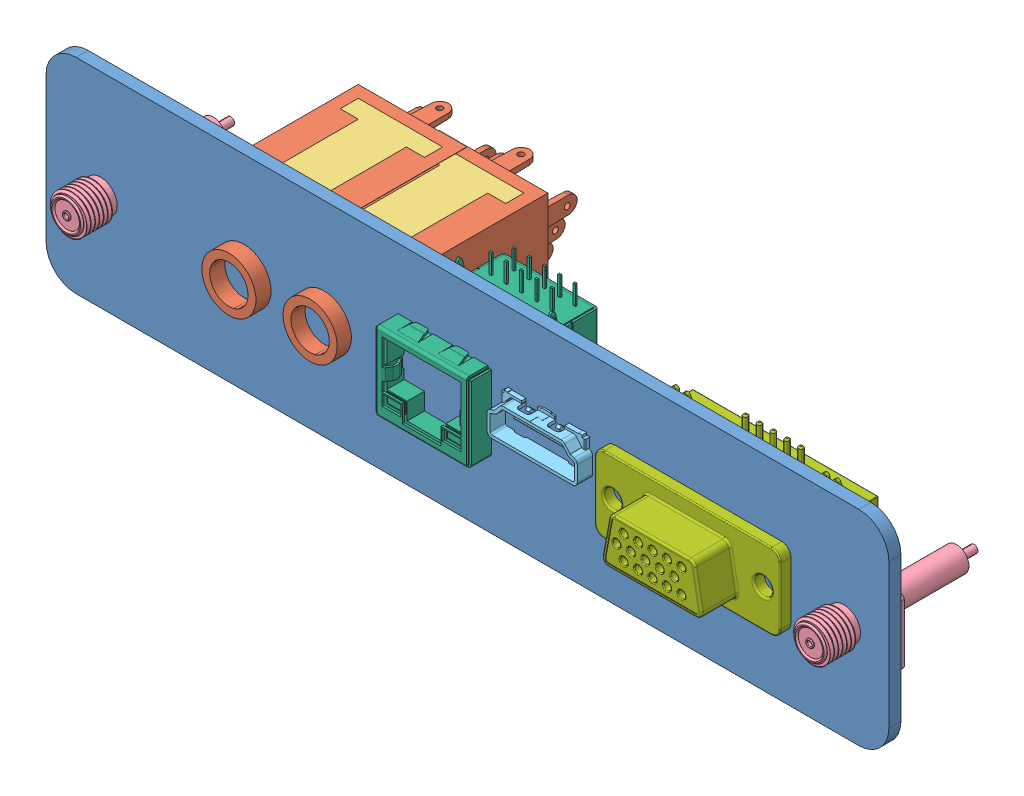
SolidWorks assembly mini computer back panel, configuration Default. Lengths in mm.
Overall size (140 34 41.82).
12 component instances, 7 part files, 10 mates.
Components (placement in the parent):
- mini computer enclosure sides-1: mini computer enclosure sides [Default] at (57.49 77.4023 100.7509) size (140 34 2)
- 6.35mm jack-1: 6.35mm jack [Default] at (20.382 76.9675 85.7703) size (19 18 36.5)
  - 6.35mm jack-1: 6.35mm jack [Default] at origin size (18 18 36.5)
  - Gnd Plate_6.35mm jack-1: Gnd Plate_6.35mm jack [Default] at (0 0 10) size (17 18 20)
- 6.35mm jack-2: 6.35mm jack [Default] at (33.7137 76.9223 85.6106) size (19 18 36.5)
  - 6.35mm jack-1: 6.35mm jack [Default] at origin size (18 18 36.5)
  - Gnd Plate_6.35mm jack-1: Gnd Plate_6.35mm jack [Default] at (0 0 10) size (17 18 20)
- Conector SMA flange 4 furos-1: Conector SMA flange 4 furos [Valor predeterminado] at (-3.4215 76.4747 99.0509) x (1 0 0) z (0 -1 0) size (12.7 27.4 12.7)
- Conector SMA flange 4 furos-2: Conector SMA flange 4 furos [Valor predeterminado] at (120.0439 76.6956 99.0509) x (1 0 0) z (0 -1 0) size (12.7 27.4 12.7)
- hdmi female-2: hdmi female [Default] at (70.798 82.8969 105.3066) x (-1 0 0) z (0 0 1) size (15.14 8.38 12.15)
- RJ45_10P_TJ3009-1: RJ45_10P_TJ3009 [Default] at (53.5571 84.0699 95.5036) x (-1 0 0) z (0 0 1) size (16 15.87 21.5)
- VGA PORT-1: VGA PORT [По умолчанию] at (95.8113 77.1031 104.5295) x (1 0 0) z (0 0 -1) size (30.8 16.47 22.2)
Mates (geometry in assembly coordinates):
- Coincident1: coincident anti-aligned: plane of mini computer enclosure sides-1 through (122.49 89.4023 100.7509) normal (0 0 -1); plane of Conector SMA flange 4 furos-2 through (120.0439 76.6956 100.7509) normal (0 0 1)
- Coincident2: coincident anti-aligned: plane of mini computer enclosure sides-1 through (122.49 89.4023 100.7509) normal (0 0 -1); plane of Conector SMA flange 4 furos-1 through (-3.4215 76.4747 100.7509) normal (0 0 1)
- Parallel1: parallel aligned: plane of Conector SMA flange 4 furos-1 through (-3.4215 76.4747 99.0509) normal (0 0 -1); plane of Conector SMA flange 4 furos-2 through (120.0439 76.6956 99.0509) normal (0 0 -1)
- Lock1: lock: unknown of mini computer enclosure sides-1; unknown of VGA PORT-1
- Lock2: lock: unknown of mini computer enclosure sides-1; unknown of 6.35mm jack-1/6.35mm jack-1
- Lock3: lock: unknown of mini computer enclosure sides-1; unknown of 6.35mm jack-2/6.35mm jack-1
- Lock4: lock: unknown of mini computer enclosure sides-1; unknown of Conector SMA flange 4 furos-2
- Lock5: lock: unknown of mini computer enclosure sides-1; unknown of hdmi female-2
- Lock6: lock: unknown of mini computer enclosure sides-1; unknown of RJ45_10P_TJ3009-1
- Lock7: lock: unknown of mini computer enclosure sides-1; unknown of Conector SMA flange 4 furos-1
